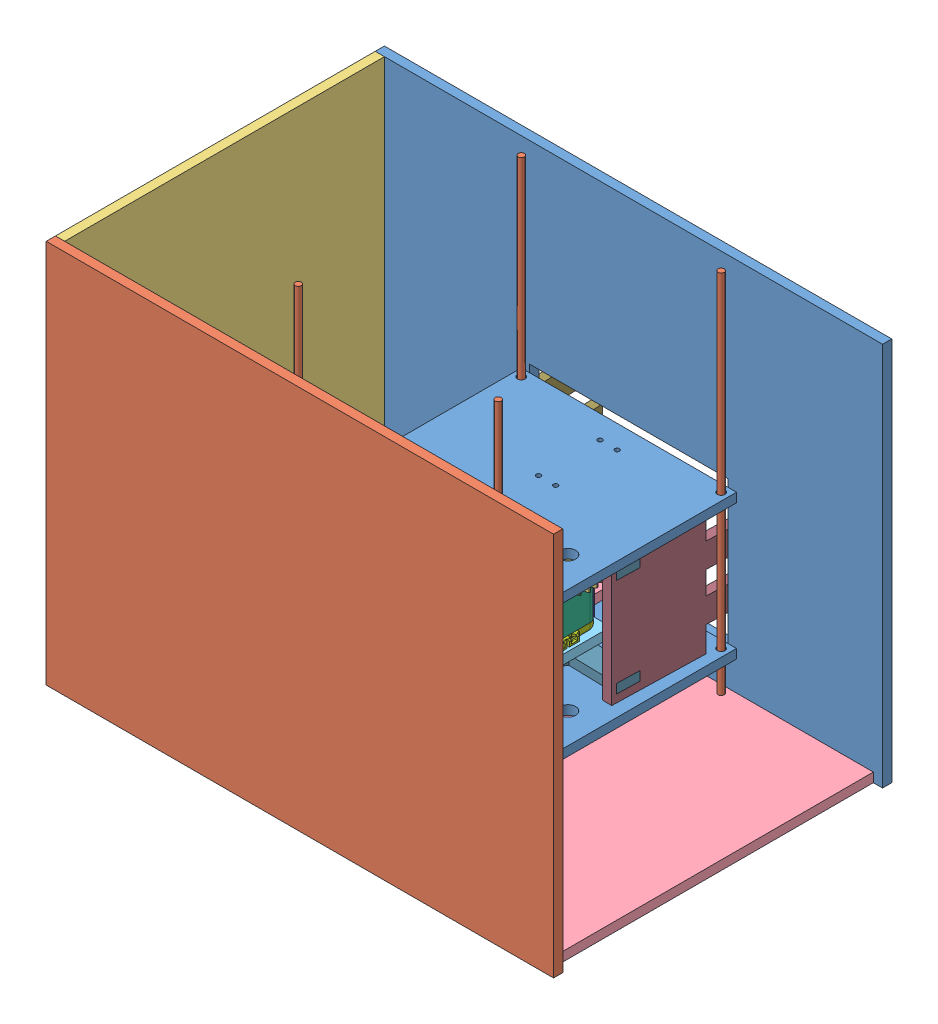
SolidWorks assembly Assemblage Carcasse, configuration Défaut. Lengths in mm.
Overall size (330 250 329.58).
52 component instances, 22 part files, 42 mates.
Components (placement in the parent):
- Carcasse axe XZ avant-1: Carcasse axe XZ avant [Défaut] at (-43.2189 -44.9147 300) size (330 250 6)
- Carcasse axe XZ arrière-1: Carcasse axe XZ arrière [Défaut] at (-43.2189 21.2284 514) size (330 250 6)
- Carcasse axe YZ-1: Carcasse axe YZ [Défaut] at (157.5448 26.7985 426.1569) x (0 0 1) z (-1 0 0) size (208 250 6) (hidden)
- Carcasse axe YZ-2: Carcasse axe YZ [Défaut] at (-172.4552 26.7985 393.8431) x (0 0 -1) z (1 0 0) size (208 250 6)
- Carcasse XY-1: Carcasse XY [Défaut] at (-7.4552 -97.0148 344.0708) x (0 0 1) z (0 1 0) size (329.58 318 6)
- Carcasse XY-3: Carcasse XY [Défaut] at (-7.4552 146.9852 344.0708) x (0 0 1) z (0 1 0) size (329.58 318 6) (hidden)
- Assemblage Pince-1: Assemblage Pince [Défaut] at (0.9771 79.1298 393.3249) x (-1 0 0) z (0 -1 0) size (134.94 250.89 82)
  - Pièce liaison Pignon Bati-1: Pièce liaison Pignon Bati [Défaut] at (6.5323 25.7104 75.0001) size (78 76 6)
  - Pièce liaison Pignon Bati-2: Pièce liaison Pignon Bati [Défaut] at (6.5323 25.7104 133.0001) x (-1 0 0) z (0 0 -1) size (78 76 6)
  - AX-12A-1: AX-12A [Default] at (21.5323 25.7104 96.0001) x (0 -1 0) z (0 0 -1) size (50 32 40.55)
    - AX-12A-01-1: AX-12A-01 [Default] at origin size (48.5 26 22)
    - AX-12A-02-1: AX-12A-02 [Default] at (0 0 13.5) size (50 32 8)
    - AX-12A-03-1: AX-12A-03 [Default] at (0 0 -13.5) x (1 0 0) z (0 0 -1) size (50 32 8)
    - AX-12A-04-1: AX-12A-04 [Default] at (0 0 21) size (22 22 6.7)
    - SetScrew-5: SetScrew [Default] at (33 10.4 14.5) x (0.31498 0.949098 0) z (0 0 -1) size (3.3 3.3 29.44)
    - SetScrew-6: SetScrew [Default] at (-9 9.25 14.5) x (0.31498 0.949098 0) z (0 0 -1) size (3.3 3.3 29.44)
    - SetScrew-7: SetScrew [Default] at (-9 -9.25 14.5) x (-0.958559 0.284893 0) z (0 0 -1) size (3.3 3.3 29.44)
    - SetScrew-8: SetScrew [Default] at (33 -10.4 14.5) x (0.31498 0.949098 0) z (0 0 -1) size (3.3 3.3 29.44)
    - pan head cross recess screw_iso-1: pan head cross recess screw_iso [ISO 7045 - M2.5 x 8 - Z --- 8C] at (0 0 21.6) x (0 0 -1) z (1 0 0) size (10.05 5 5)
  - AX-12A-2: AX-12A [Default] at (-8.4677 25.7104 112.0001) x (0 -1 0) z (0 0 1) size (50 32 40.55)
    - AX-12A-01-1: AX-12A-01 [Default] at origin size (48.5 26 22)
    - AX-12A-02-1: AX-12A-02 [Default] at (0 0 13.5) size (50 32 8)
    - AX-12A-03-1: AX-12A-03 [Default] at (0 0 -13.5) x (1 0 0) z (0 0 -1) size (50 32 8)
    - AX-12A-04-1: AX-12A-04 [Default] at (0 0 21) size (22 22 6.7)
    - SetScrew-5: SetScrew [Default] at (33 10.4 14.5) x (0.31498 0.949098 0) z (0 0 -1) size (3.3 3.3 29.44)
    - SetScrew-6: SetScrew [Default] at (-9 9.25 14.5) x (0.31498 0.949098 0) z (0 0 -1) size (3.3 3.3 29.44)
    - SetScrew-7: SetScrew [Default] at (-9 -9.25 14.5) x (-0.958559 0.284893 0) z (0 0 -1) size (3.3 3.3 29.44)
    - SetScrew-8: SetScrew [Default] at (33 -10.4 14.5) x (0.31498 0.949098 0) z (0 0 -1) size (3.3 3.3 29.44)
    - pan head cross recess screw_iso-1: pan head cross recess screw_iso [ISO 7045 - M2.5 x 8 - Z --- 8C] at (0 0 21.6) x (0 0 -1) z (1 0 0) size (10.05 5 5)
  - Pièce pince facette A-1: Pièce pince facette A [Défaut] at (69.878 86.0751 87.0676) x (0 0 -1) z (0.999246 -0.038824 0) size (80 120 6)
  - Pièce pince facette B-1: Pièce pince facette B [Défaut] at (-56.0309 86.0867 87.0676) x (0 0 -1) z (0.999679 0.025342 0) size (80 120 6)
  - Pignon facette A-1: Pignon facette A [ISO - Spur gear 1.5M 20T 20PA 6FW ---S20A75H50L10.0N] at (-8.4677 25.7104 75.0001) x (0 0 -1) z (0.999679 0.025342 0) size (6 32.71 62.37)
  - Pignon facette A-2: Pignon facette A [ISO - Spur gear 1.5M 20T 20PA 6FW ---S20A75H50L10.0N] at (-8.4677 25.7104 139.0001) x (0 0 -1) z (0.999679 0.025342 0) size (6 32.71 62.37)
  - Pignon facette B-1: Pignon facette B [ISO - Spur gear 1.5M 20T 20PA 6FW ---S20A75H50L10.0N] at (21.5323 25.7104 69) x (0 0 1) z (-0.993017 -0.117971 0) size (6 32.71 62.94)
  - Pignon facette B-2: Pignon facette B [ISO - Spur gear 1.5M 20T 20PA 6FW ---S20A75H50L10.0N] at (21.5323 25.7104 133.0001) x (0 0 1) z (-0.993017 -0.117971 0) size (6 32.71 62.94)
  - Glissière axe Y-1: Glissière axe Y [ISO - Rack-spur - rectangular 1.5M 20PA 6FW 25PH 150L---SAll] at (-1.9677 8.7104 63.0001) x (0 -1 0) z (0 0 -1) size (126 26.5 6)
  - Glissière axe Y-2: Glissière axe Y [ISO - Rack-spur - rectangular 1.5M 20PA 6FW 25PH 150L---SAll] at (15.0323 8.7104 145) x (0 -1 0) z (0 0 1) size (126 26.5 6)
  - Pièce renfort-1: Pièce renfort [Défaut] at (6.5323 40.7104 97.0001) x (1 0 0) z (0 1 0) size (33 58 6)
  - Pièce renfort-2: Pièce renfort [Défaut] at (45.5323 -12.7896 97.0001) x (0 1 0) z (-1 0 0) size (33 58 6)
  - Pièce renfort-3: Pièce renfort [Défaut] at (-32.4677 -12.7896 97.0001) x (0 -1 0) z (1 0 0) size (33 58 6)
  - Support Surélève cremaillère-1: Support Surélève cremaillère [Défaut] at (30.8337 -8.6826 133.0001) size (22 30 6)
  - Support Surélève cremaillère-2: Support Surélève cremaillère [Défaut] at (-9.1663 -8.6826 69) size (22 30 6)
- Maintient de Pince-1: Maintient de Pince [Défaut] at (-1.9552 16.1298 383.5) x (0 0 -1) z (0 1 0) size (155 140 6)
- Maintient de Pince-2: Maintient de Pince [Défaut] at (-1.9552 -71.8702 383.5) x (0 0 -1) z (0 1 0) size (155 140 6)
- Tige de maintient axe Z-1: Tige de maintient axe Z [Défaut] at (57.5448 146.9852 311) x (0.981328 0 0.192341) z (0 -1 0) size (4 4 238)
- Tige de maintient axe Z-2: Tige de maintient axe Z [Défaut] at (-72.4552 146.9852 311) x (1 0 0) z (0 -1 0) size (4 4 238)
- Tige de maintient axe Z-3: Tige de maintient axe Z [Défaut] at (-72.4552 146.9852 456) x (1 0 0) z (0 -1 0) size (4 4 238)
- Tige de maintient axe Z-4: Tige de maintient axe Z [Défaut] at (57.5448 146.9852 456) x (1 0 0) z (0 -1 0) size (4 4 238)
- Pignon Glissière axe Y et Z-1: Pignon Glissière axe Y et Z [ISO - Spur gear 1.5M 20T 20PA 6FW ---S20A75H50L10.0N] at (42.9448 10.1298 396) x (0 1 0) z (0.823235 0 0.5677) size (6 32.71 32.71)
- Pignon Glissière axe Y et Z-2: Pignon Glissière axe Y et Z [ISO - Spur gear 1.5M 20T 20PA 6FW ---S20A75H50L10.0N] at (-54.4152 -59.8702 396) x (0 -1 0) z (-0.609994 0 0.792406) size (6 32.71 32.71)
- Renfort pour liaison glissière-3: Renfort pour liaison glissière [Défaut] at (13.9351 10.1298 370.5971) x (0 0 -1) z (0 1 0) size (110 6 6)
- Renfort pour liaison glissière-4: Renfort pour liaison glissière [Défaut] at (-25.2055 -59.8702 370.5971) x (0 0 -1) z (0 -1 0) size (110 6 6)
Mates (geometry in assembly coordinates):
- Perpendiculaire1: perpendicular: plane of Carcasse axe XZ arrière-1 through (-43.2189 21.2284 514) normal (0 0 -1); plane of Carcasse axe YZ-2 through (-172.4552 26.7985 393.8431) normal (-1 0 0)
- Coïncidente6: coincident anti-aligned: line of Carcasse axe XZ arrière-1 through (-172.4552 152.9852 520) axis (0 0 -1); line of Carcasse axe YZ-2 through (-172.4552 152.9852 306) axis (0 0 1)
- Perpendiculaire2: perpendicular: plane of Carcasse axe XZ arrière-1 through (-43.2189 21.2284 514) normal (0 0 -1); plane of Carcasse axe YZ-1 through (157.5448 26.7985 426.1569) normal (1 0 0)
- Coïncidente8: coincident aligned: line of Carcasse axe XZ arrière-1 through (157.5448 152.9852 520) axis (0 0 -1); line of Carcasse axe YZ-1 through (157.5448 152.9852 514) axis (0 0 -1)
- Coïncidente9: coincident anti-aligned: line of Carcasse axe XZ arrière-1 through (157.5448 152.9852 514) axis (-1 0 0); line of Carcasse axe YZ-1 through (151.5448 152.9852 514) axis (1 0 0)
- Coïncidente10: coincident anti-aligned: line of Carcasse axe XZ avant-1 through (157.5448 152.9852 306) axis (-1 0 0); line of Carcasse axe YZ-1 through (151.5448 152.9852 306) axis (1 0 0)
- Coïncidente11: coincident aligned: line of Carcasse axe XZ avant-1 through (157.5448 152.9852 306) axis (-1 0 0); line of Carcasse axe YZ-2 through (-166.4552 152.9852 306) axis (-1 0 0)
- Coïncidente12: coincident aligned: line of Carcasse axe XZ avant-1 through (157.5448 152.9852 306) axis (0 0 -1); line of Carcasse axe YZ-1 through (157.5448 152.9852 514) axis (0 0 -1)
- Coïncidente47: coincident anti-aligned: line of Carcasse axe YZ-1 through (151.5448 -97.0148 306) axis (0 0 1); line of Carcasse XY-1 through (151.5448 -97.0148 514) axis (0 0 -1)
- Coïncidente48: coincident anti-aligned: line of Carcasse axe XZ avant-1 through (-172.4552 -97.0148 306) axis (1 0 0); line of Carcasse XY-1 through (151.5448 -97.0148 306) axis (-1 0 0)
- Coïncidente59: coincident anti-aligned: line of Carcasse axe XZ arrière-1 through (157.5448 152.9852 514) axis (-1 0 0); line of Carcasse XY-3 through (-166.4552 152.9852 514) axis (1 0 0)
- Coïncidente60: coincident aligned: line of Carcasse axe YZ-2 through (-166.4552 152.9852 306) axis (0 0 1); line of Carcasse XY-3 through (-166.4552 152.9852 306) axis (0 0 1)
- Coïncidente67: coincident anti-aligned: plane of Carcasse axe XZ avant-1 through (-43.2189 -44.9147 306) normal (0 0 1); plane of Maintient de Pince-1 through (-77.4552 22.1298 306) normal (0 0 -1)
- Parallèle3: parallel anti-aligned: plane of Carcasse axe YZ-2 through (-166.4552 26.7985 393.8431) normal (1 0 0); plane of Maintient de Pince-1 through (-77.4552 22.1298 461) normal (-1 0 0)
- Parallèle5: parallel anti-aligned: plane of Carcasse axe XZ avant-1 through (57.0448 26.9852 306) normal (-1 0 0); plane of Maintient de Pince-1 through (62.5448 22.1298 461) normal (1 0 0)
- Coïncidente73: coincident anti-aligned: plane of Carcasse axe XZ avant-1 through (-43.2189 -44.9147 306) normal (0 0 1); plane of Maintient de Pince-2 through (-77.4552 -65.8702 306) normal (0 0 -1)
- Parallèle7: parallel anti-aligned: plane of Carcasse axe YZ-2 through (-166.4552 26.7985 393.8431) normal (1 0 0); plane of Maintient de Pince-2 through (-77.4552 -65.8702 461) normal (-1 0 0)
- Coaxiale1: concentric anti-aligned: cylinder of Maintient de Pince-1 through (57.5448 22.1298 311) axis (0 -1 0) radius 2.5; cylinder of Tige de maintient axe Z-1 through (57.5448 -91.0148 311) axis (0 1 0) radius 2
- Coaxiale2: concentric anti-aligned: cylinder of Maintient de Pince-2 through (57.5448 -65.8702 311) axis (0 -1 0) radius 2.5; cylinder of Tige de maintient axe Z-1 through (57.5448 -91.0148 311) axis (0 1 0) radius 2
- Coaxiale3: concentric anti-aligned: cylinder of Maintient de Pince-1 through (-72.4552 22.1298 311) axis (0 -1 0) radius 2.5; cylinder of Tige de maintient axe Z-2 through (-72.4552 -91.0148 311) axis (0 1 0) radius 2
- Coaxiale4: concentric anti-aligned: cylinder of Maintient de Pince-1 through (-72.4552 22.1298 456) axis (0 -1 0) radius 2.5; cylinder of Tige de maintient axe Z-3 through (-72.4552 -91.0148 456) axis (0 1 0) radius 2
- Coaxiale6: concentric anti-aligned: cylinder of Maintient de Pince-1 through (57.5448 22.1298 456) axis (0 -1 0) radius 2.5; cylinder of Tige de maintient axe Z-4 through (57.5448 -91.0148 456) axis (0 1 0) radius 2
- Coïncidente76: coincident anti-aligned: plane of Carcasse XY-1 through (-7.4552 -91.0148 344.0708) normal (0 1 0); plane of Tige de maintient axe Z-4 through (57.5448 -91.0148 456) normal (0 -1 0)
- Coïncidente77: coincident anti-aligned: plane of Carcasse XY-1 through (-7.4552 -91.0148 344.0708) normal (0 1 0); plane of Tige de maintient axe Z-1 through (57.5448 -91.0148 311) normal (0 -1 0)
- Coïncidente78: coincident anti-aligned: plane of Carcasse XY-1 through (-7.4552 -91.0148 344.0708) normal (0 1 0); plane of Tige de maintient axe Z-2 through (-72.4552 -91.0148 311) normal (0 -1 0)
- Coïncidente79: coincident anti-aligned: plane of Carcasse XY-1 through (-7.4552 -91.0148 344.0708) normal (0 1 0); plane of Tige de maintient axe Z-3 through (-72.4552 -91.0148 456) normal (0 -1 0)
- Coïncidente80: coincident anti-aligned: plane of Maintient de Pince-1 through (-1.9552 16.1298 383.5) normal (0 -1 0); plane of Pignon Glissière axe Y et Z-1 through (42.9448 16.1298 396) normal (0 1 0)
- Coïncidente81: coincident anti-aligned: plane of Maintient de Pince-2 through (-1.9552 -65.8702 383.5) normal (0 1 0); plane of Pignon Glissière axe Y et Z-2 through (-54.4152 -65.8702 396) normal (0 -1 0)
- Coaxiale7: concentric aligned: cylinder of Maintient de Pince-1 through (42.9448 22.1298 396) axis (0 -1 0) radius 5; cylinder of Pignon Glissière axe Y et Z-1 through (42.9448 60.1298 396) axis (0 -1 0) radius 5
- Coaxiale8: concentric anti-aligned: cylinder of Maintient de Pince-2 through (-54.4152 -65.8702 396) axis (0 -1 0) radius 5; cylinder of Pignon Glissière axe Y et Z-2 through (-54.4152 -109.8703 396) axis (0 1 0) radius 5
- Coïncidente82: coincident anti-aligned: plane of Assemblage Pince-1/Glissière axe Y-1 through (29.4448 16.1298 384.6146) normal (0 1 0); plane of Maintient de Pince-1 through (-1.9552 16.1298 383.5) normal (0 -1 0)
- Coïncidente89: coincident anti-aligned: plane of Assemblage Pince-1/Glissière axe Y-2 through (-40.5552 -65.8702 384.6146) normal (0 -1 0); plane of Maintient de Pince-2 through (-1.9552 -65.8702 383.5) normal (0 1 0)
- Distance1: distance = 89 mm anti-aligned: plane of Carcasse axe YZ-2 through (-166.4552 26.7985 393.8431) normal (1 0 0); plane of Maintient de Pince-1 through (-77.4552 22.1298 461) normal (-1 0 0)
- RackPinionMate3: rack pinion = 30 mm: line of Assemblage Pince-1/Glissière axe Y-1 through (2.9448 16.1298 384.6146) axis (0 0 1); circle of Pignon Glissière axe Y et Z-1
- RackPinionMate4: rack pinion = 30 mm: line of Assemblage Pince-1/Glissière axe Y-2 through (-14.0552 -59.8702 384.6146) axis (0 0 1); circle of Pignon Glissière axe Y et Z-2
- Coïncidente94: coincident anti-aligned: plane of Maintient de Pince-1 through (-1.9552 16.1298 383.5) normal (0 -1 0); plane of Renfort pour liaison glissière-3 through (13.9351 16.1298 370.5971) normal (0 1 0)
- Coaxiale14: concentric aligned: cylinder of Maintient de Pince-1 through (-0.0552 16.1298 321) axis (0 1 0) radius 1.5; cylinder of Renfort pour liaison glissière-3 through (-0.0552 13.1298 321) axis (0 1 0) radius 1.5
- Coaxiale15: concentric aligned: cylinder of Maintient de Pince-1 through (-0.0552 16.1298 401) axis (0 1 0) radius 1.5; cylinder of Renfort pour liaison glissière-3 through (-0.0552 13.1298 401) axis (0 1 0) radius 1.5
- Coïncidente96: coincident anti-aligned: plane of Assemblage Pince-1/Glissière axe Y-1 through (2.9448 10.1298 384.6146) normal (-1 0 0); plane of Renfort pour liaison glissière-3 through (2.9448 16.1298 416) normal (1 0 0)
- Coïncidente97: coincident anti-aligned: plane of Maintient de Pince-2 through (-1.9552 -65.8702 383.5) normal (0 1 0); plane of Renfort pour liaison glissière-4 through (-25.2055 -65.8702 370.5971) normal (0 -1 0)
- Coaxiale16: concentric anti-aligned: cylinder of Maintient de Pince-2 through (-11.2152 -71.8702 401) axis (0 1 0) radius 1.5; cylinder of Renfort pour liaison glissière-4 through (-11.2152 -62.8702 401) axis (0 -1 0) radius 1.5
- Coaxiale17: concentric anti-aligned: cylinder of Maintient de Pince-2 through (-11.2152 -71.8702 321) axis (0 1 0) radius 1.5; cylinder of Renfort pour liaison glissière-4 through (-11.2152 -62.8702 321) axis (0 -1 0) radius 1.5
